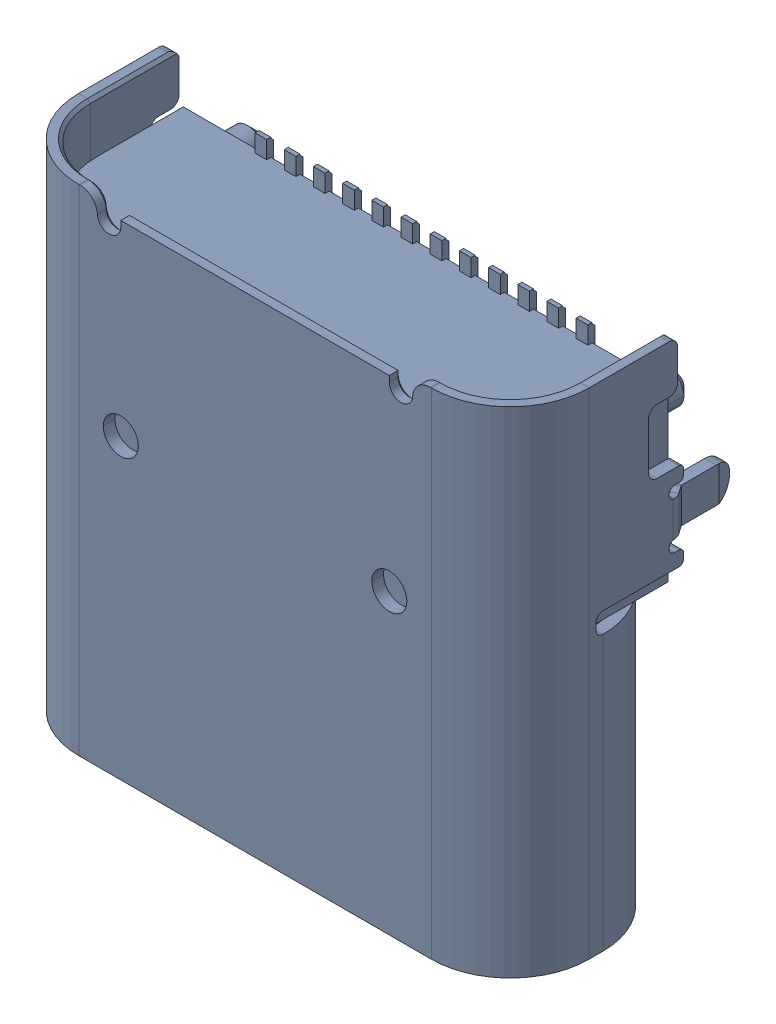
SolidWorks assembly AS0605401_ASM_4_ASM, configuration AS0605401_ASM_4_ASM. Lengths in mm.
Overall size (8.74 8.48 3.97).
2 component instances, 1 part files, 0 mates.
Components (placement in the parent):
- 10137062C_1_ASM_2_ASM-1: 10137062C_1_ASM_2_ASM [10137062C_1_ASM_2_ASM] at (-37.01 -9 -21.3) x (1 0 0) z (0 -1 0) size (8.74 3.97 8.48)
  - 10137062C_1_1_1-1: 10137062C_1_1_1 [10137062C_1_1_1] at origin size (8.74 3.97 8.48)
